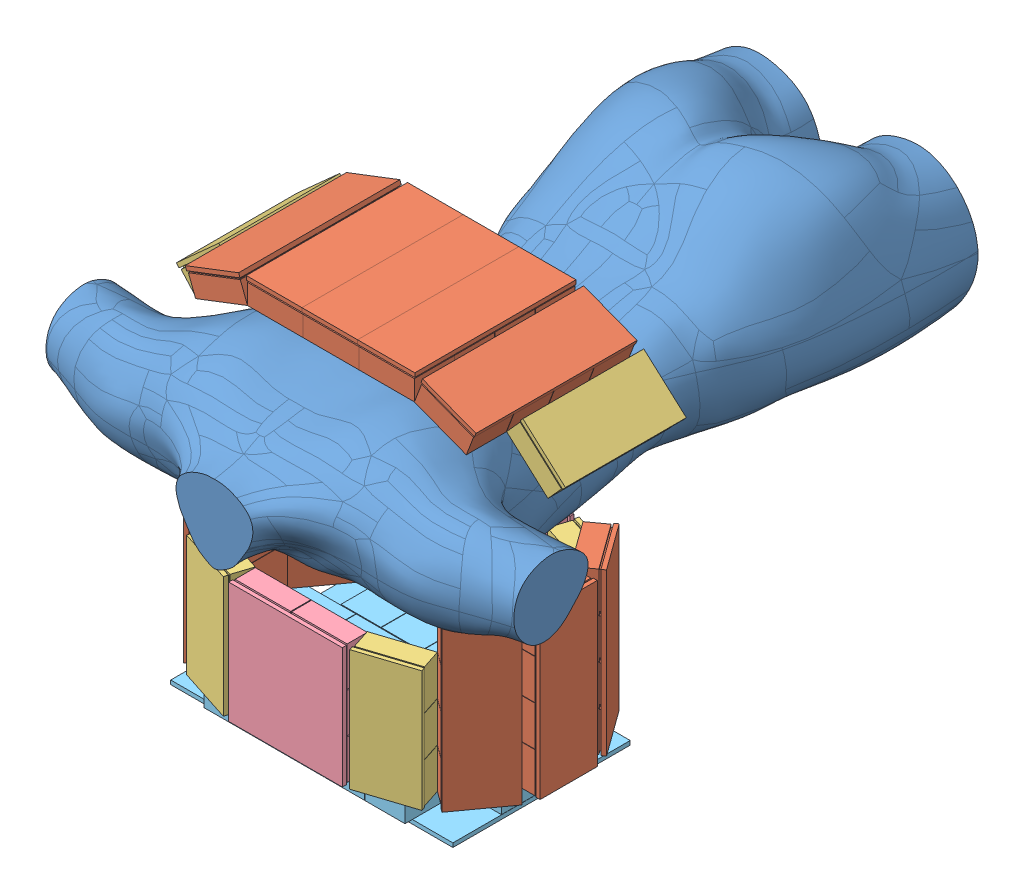
SolidWorks assembly BODYdetector2, configuration Default. Lengths in mm.
Overall size (637.83 463.18 817.55).
26 component instances, 5 part files, 0 mates.
Components (placement in the parent):
- woman body-1: woman body [Default] at (325.4407 484.4544 221.086) size (637.83 301.02 817.55)
- Detector_posterial-1: Detector_posterial [Default] at (222.7152 722.4354 904.6015) x (1 0 0) z (0 0 -1) size (482.7 103.57 200)
  - 1Detector-1: 1Detector [Default] at (83.9721 85.3161 150.6758) size (71 32 200)
  - 1Detector-2: 1Detector [Default] at (152.9721 85.3161 150.6758) size (71 32 200)
  - 1Detector-3: 1Detector [Default] at (14.9721 85.3161 150.6758) size (71 32 200)
  - 1Detector-4: 1Detector [Default] at (-63.2042 99.8052 150.6758) x (0.93358 -0.358368 0) z (0 0 1) size (71 32 200)
  - 1Detector-5: 1Detector [Default] at (231.1484 99.8052 150.6758) x (0.93358 0.358368 0) z (0 0 1) size (71 32 200)
  - 1Detector_3modules-1: 1Detector_3modules [Default] at (-130.9957 141.3479 175.6758) x (0.743145 -0.669131 0) z (0 0 1) size (71 32 150)
  - 1Detector_3modules-2: 1Detector_3modules [Default] at (298.9398 141.3479 175.6758) x (0.743145 0.669131 0) z (0 0 1) size (71 32 150)
- Detector1n2_3-1: Detector1n2_3 [Default] at (74.7015 639.6953 479.9147) x (1 0 0) z (0 -1 0) size (495.24 340.33 231)
  - Detector1n2_changed-1: Detector1n2_changed [Default] at (192.5923 83.3442 236.3919) size (495.24 340.33 200.99)
    - top_bottomDetector2-1: top_bottomDetector2 [Default] at (5.3043 60.2155 74.3483) size (141 32 149.74)
    - CshapedDetector2-1: CshapedDetector2 [Default] at (104.3454 -76.5763 -85.899) x (0.951057 0.309017 0) z (0 0 1) size (177.89 270.84 200)
      - 1Detector-2: 1Detector [Default] at (173.0714 153.2337 184.2598) x (0.809017 0.587785 0) z (0 0 1) size (71 32 200)
      - 1Detector-4: 1Detector [Default] at (223.2683 222.3237 184.2598) x (0.309017 0.951057 0) z (0 0 1) size (71 32 200)
      - 1Detector-5: 1Detector [Default] at (223.2683 307.7237 184.2598) x (-0.309017 0.951057 0) z (0 0 1) size (71 32 200)
      - 1Detector_3modules-1: 1Detector_3modules [Default] at (91.8512 126.8436 209.2598) size (71 32 150)
      - 1Detector_3modules-2: 1Detector_3modules [Default] at (173.0714 376.8138 209.2598) x (-0.809017 0.587785 0) z (0 0 1) size (71 32 150)
    - CshapedDetector2-2: CshapedDetector2 [Default] at (-23.7368 484.2959 -85.899) x (-0.951057 -0.309017 0) z (0 0 1) size (177.89 270.84 200)
      - 1Detector-2: 1Detector [Default] at (173.0714 153.2337 184.2598) x (0.809017 0.587785 0) z (0 0 1) size (71 32 200)
      - 1Detector-4: 1Detector [Default] at (223.2683 222.3237 184.2598) x (0.309017 0.951057 0) z (0 0 1) size (71 32 200)
      - 1Detector-5: 1Detector [Default] at (223.2683 307.7237 184.2598) x (-0.309017 0.951057 0) z (0 0 1) size (71 32 200)
      - 1Detector_3modules-1: 1Detector_3modules [Default] at (91.8512 126.8436 209.2598) size (71 32 150)
      - 1Detector_3modules-2: 1Detector_3modules [Default] at (173.0714 376.8138 209.2598) x (-0.809017 0.587785 0) z (0 0 1) size (71 32 150)
    - top_bottomDetector2-2: top_bottomDetector2 [Default] at (75.3043 347.5042 74.3483) x (-1 0 0) z (0 0 1) size (141 32 149.74)
  - Detector3-1: Detector3 [Default] at (231.9665 287.248 465.7527) x (0 -1 0) z (1 0 0) size (239.5 31 350)
